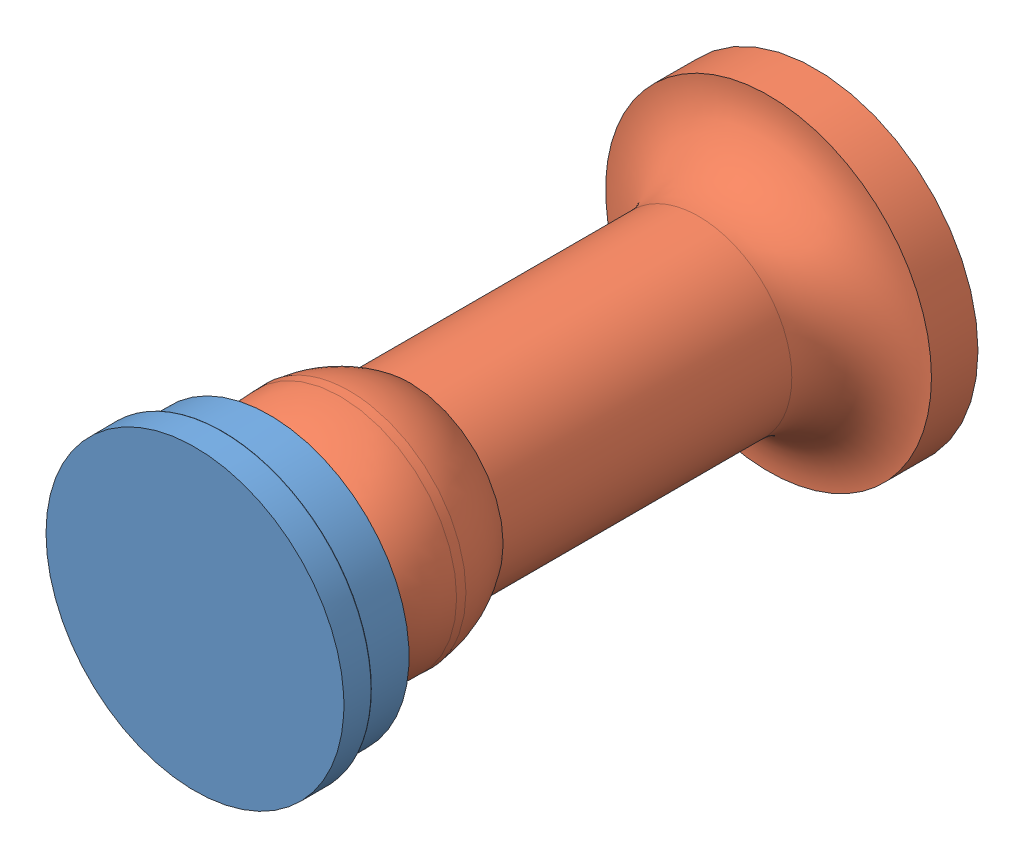
SolidWorks assembly asem proj, configuration Default. Lengths in mm.
Overall size (35 35 67.27).
2 component instances, 2 part files, 1 mates.
Components (placement in the parent):
- holder-1: holder [Default] at (2.3467 17.4861 33.0502) size (32 32 8)
- arm-1: arm [Default] at (1.6916 17.248 -26.2156) size (35 35 63.5)
Mates (geometry in assembly coordinates):
- Lock1: lock: unknown of holder-1; unknown of arm-1
